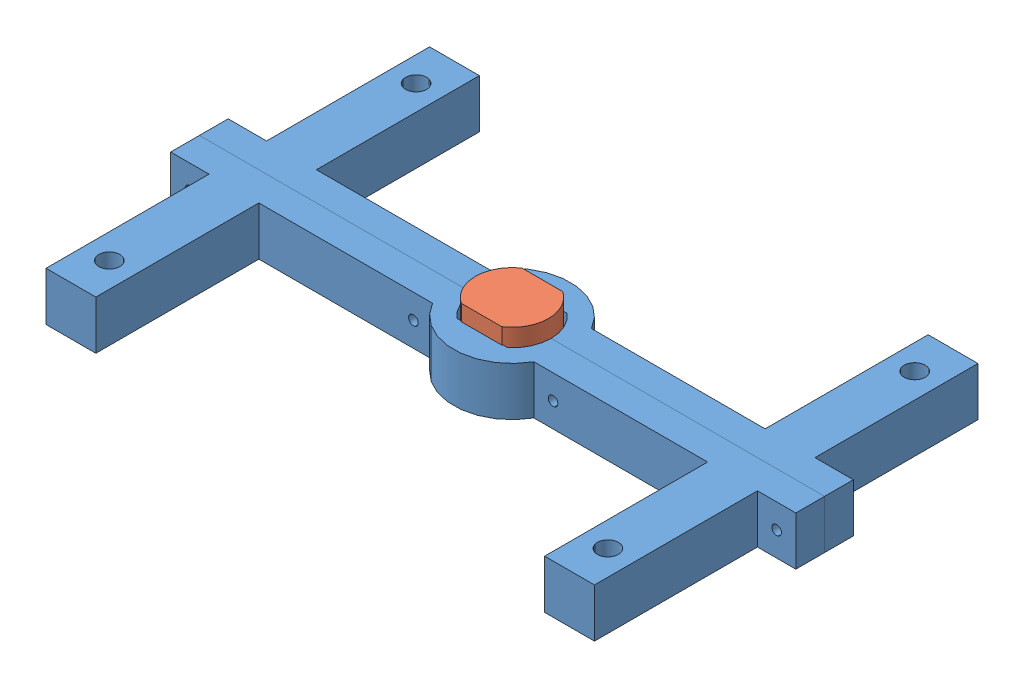
SolidWorks assembly 3dprint test motor holder, configuration Default. Lengths in mm.
Overall size (163 20.96 100).
11 component instances, 4 part files, 23 mates.
Components (placement in the parent):
- 3Dprint testmotor-1: 3Dprint testmotor [Default] at (-22.3496 92.4113 164.0235) size (163 12.7 50)
- 3Dprint testmotor-2: 3Dprint testmotor [Default] at (127.6504 92.4113 64.0235) x (-1 0 0) z (0 0 -1) size (163 12.7 50)
- testmotor-1: testmotor [Default] at (52.6504 109.276 114.0235) x (-1 0 0) z (0 0 1) size (19.05 20.96 15.88)
- hex nut style 1_am-5: hex nut style 1_am [B18.2.4.1M - Hex nut, Style 1,  M2.5 x 0.45 --D-N] at (70.8504 98.7613 106.5235) (suppressed, hidden)
- hex nut style 1_am-6: hex nut style 1_am [B18.2.4.1M - Hex nut, Style 1,  M2.5 x 0.45 --D-N] at (129.1504 98.7613 106.5235) (suppressed, hidden)
- hex nut style 1_am-7: hex nut style 1_am [B18.2.4.1M - Hex nut, Style 1,  M2.5 x 0.45 --D-N] at (34.4504 98.7613 106.5235) (suppressed, hidden)
- hex nut style 1_am-8: hex nut style 1_am [B18.2.4.1M - Hex nut, Style 1,  M2.5 x 0.45 --D-N] at (-23.8496 98.7613 106.5235) (suppressed, hidden)
- hex screw_am-1: hex screw_am [B18.6.7M - M2.5 x 0.45 x 20 Indented HHMS --20N] at (129.1504 98.7613 123.6235) x (0 0 -1) z (1 0 0) (suppressed, hidden)
- hex screw_am-2: hex screw_am [B18.6.7M - M2.5 x 0.45 x 20 Indented HHMS --20N] at (34.4504 98.7613 123.6235) x (0 0 -1) z (-0.113289 0.993562 0) (suppressed, hidden)
- hex screw_am-3: hex screw_am [B18.6.7M - M2.5 x 0.45 x 20 Indented HHMS --20N] at (-23.8496 98.7613 123.6235) x (0 0 -1) z (1 0 0) (suppressed, hidden)
- hex screw_am-4: hex screw_am [B18.6.7M - M2.5 x 0.45 x 20 Indented HHMS --20N] at (70.8504 98.7613 123.6235) x (0 0 -1) z (0.574215 0.818705 0) (suppressed, hidden)
Mates (geometry in assembly coordinates):
- Coincident1: coincident anti-aligned: plane of 3Dprint testmotor-1 through (-22.3496 75.1113 114.0235) normal (0 0 -1); plane of 3Dprint testmotor-2 through (127.6504 75.1113 114.0235) normal (0 0 1)
- Coincident2: coincident aligned: plane of 3Dprint testmotor-1 through (-22.3496 105.1113 164.0235) normal (0 1 0); plane of 3Dprint testmotor-2 through (127.6504 105.1113 64.0235) normal (0 1 0)
- Coincident3: coincident aligned: plane of 3Dprint testmotor-1 through (134.1504 92.4113 164.0235) normal (1 0 0); plane of 3Dprint testmotor-2 through (134.1504 92.4113 64.0235) normal (1 0 0)
- Concentric1: concentric aligned: cylinder of 3Dprint testmotor-1 through (52.6504 92.4113 114.0235) axis (0 1 0) radius 10.2; cylinder of testmotor-1 through (52.6504 102.926 114.0235) axis (0 1 0) radius 9.525
- Parallel1: parallel anti-aligned: plane of 3Dprint testmotor-1 through (-22.3496 92.4113 121.7735) normal (0 0 -1); plane of testmotor-1 through (52.6504 102.926 121.961) normal (0 0 1)
- Concentric3: concentric anti-aligned: cylinder of 3Dprint testmotor-2 through (70.8504 98.7613 74.0235) axis (0 0 1) radius 1.25; cylinder of formed hex screw_am-4 through (70.8504 98.7613 102.3735) axis (0 0 -1) radius 3
- Coincident5: coincident anti-aligned: plane of 3Dprint testmotor-2 through (127.6504 75.1113 106.5235) normal (0 0 -1); plane of formed hex screw_am-4 through (76.1864 96.5567 106.5235) normal (0 0 1)
- Concentric4: concentric anti-aligned: cylinder of 3Dprint testmotor-1 through (129.1504 98.7613 154.0235) axis (0 0 -1) radius 1.25; cylinder of hex screw_am-1 through (129.1504 98.7613 149.0235) axis (0 0 1) radius 1.25
- Coincident6: coincident anti-aligned: plane of 3Dprint testmotor-1 through (134.1504 92.4113 121.5235) normal (0 0 1); plane of hex screw_am-1 through (129.1504 100.0113 121.5235) normal (0 0 -1)
- Coincident7: coincident anti-aligned: plane of 3Dprint testmotor-2 through (134.1504 92.4113 106.5235) normal (0 0 -1); plane of hex nut style 1_am-6 through (129.1504 101.6481 106.5235) normal (0 0 1)
- Concentric6: concentric aligned: cylinder of hex nut style 1_am-6 through (129.1504 98.7613 104.5235) axis (0 0 1) radius 1.025; cylinder of hex screw_am-1 through (129.1504 98.7613 149.0235) axis (0 0 1) radius 1.25
- Concentric7: concentric anti-aligned: cylinder of 3Dprint testmotor-1 through (70.8504 98.7613 154.0235) axis (0 0 -1) radius 1.25; cylinder of hex screw_am-4 through (70.8504 98.7613 149.0235) axis (0 0 1) radius 1.25
- Coincident8: coincident anti-aligned: plane of 3Dprint testmotor-1 through (-22.3496 75.1113 121.5235) normal (0 0 1); plane of hex screw_am-4 through (69.827 99.4791 121.5235) normal (0 0 -1)
- Coincident9: coincident anti-aligned: plane of 3Dprint testmotor-2 through (127.6504 75.1113 106.5235) normal (0 0 -1); plane of hex nut style 1_am-5 through (70.8504 101.6481 106.5235) normal (0 0 1)
- Concentric8: concentric aligned: cylinder of hex nut style 1_am-5 through (70.8504 98.7613 104.5235) axis (0 0 1) radius 1.025; cylinder of hex screw_am-4 through (70.8504 98.7613 149.0235) axis (0 0 1) radius 1.25
- Concentric9: concentric anti-aligned: cylinder of 3Dprint testmotor-1 through (34.4504 98.7613 154.0235) axis (0 0 -1) radius 1.25; cylinder of hex screw_am-2 through (34.4504 98.7613 149.0235) axis (0 0 1) radius 1.25
- Coincident10: coincident anti-aligned: plane of 3Dprint testmotor-1 through (-22.3496 75.1113 121.5235) normal (0 0 1); plane of hex screw_am-2 through (33.2085 98.6197 121.5235) normal (0 0 -1)
- Coincident11: coincident anti-aligned: plane of 3Dprint testmotor-2 through (127.6504 75.1113 106.5235) normal (0 0 -1); plane of hex nut style 1_am-7 through (34.4504 101.6481 106.5235) normal (0 0 1)
- Concentric10: concentric aligned: cylinder of hex nut style 1_am-7 through (34.4504 98.7613 104.5235) axis (0 0 1) radius 1.025; cylinder of hex screw_am-2 through (34.4504 98.7613 149.0235) axis (0 0 1) radius 1.25
- Coincident14: coincident anti-aligned: plane of 3Dprint testmotor-1 through (-28.8496 92.4113 121.5235) normal (0 0 1); plane of hex screw_am-3 through (-23.8496 100.0113 121.5235) normal (0 0 -1)
- Concentric11: concentric anti-aligned: cylinder of 3Dprint testmotor-1 through (-23.8496 98.7613 154.0235) axis (0 0 -1) radius 1.25; cylinder of hex screw_am-3 through (-23.8496 98.7613 149.0235) axis (0 0 1) radius 1.25
- Coincident15: coincident anti-aligned: plane of 3Dprint testmotor-2 through (-28.8496 92.4113 106.5235) normal (0 0 -1); plane of hex nut style 1_am-8 through (-23.8496 101.6481 106.5235) normal (0 0 1)
- Concentric12: concentric aligned: circle of hex nut style 1_am-8; cylinder of hex screw_am-3 through (-23.8496 98.7613 149.0235) axis (0 0 1) radius 1.25
